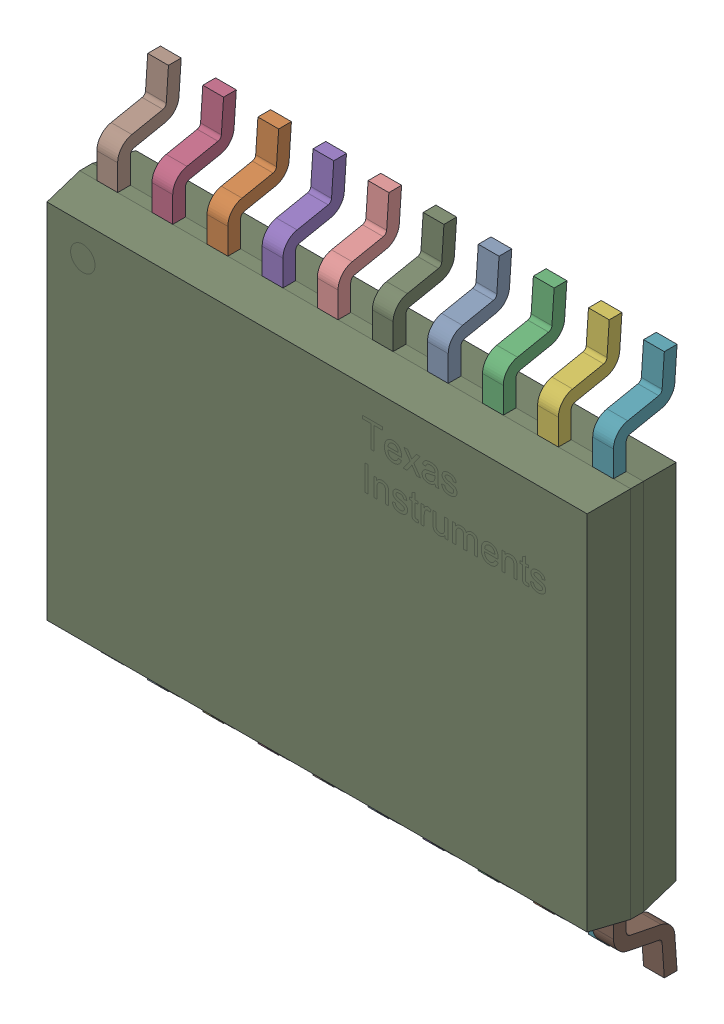
SolidWorks assembly Copy of IC_Texas_Instruments_TXS0108EQPWRQ1_eec^Copy of U3_PMPi-PCB, configuration Default. Lengths in mm.
Overall size (6.5 6.4 1.2).
21 component instances, 3 part files, 0 mates.
Components (placement in the parent):
- Copy of Texas Instruments TXS0108EQPWRQ1 2_MIR^Copy of IC_Texas_Instruments_TXS0108EQPWRQ1_eec_Copy of U3_PMPi-PCB-1: Copy of Texas Instruments TXS0108EQPWRQ1 2_MIR^Copy of IC_Texas_Instruments_TXS0108EQPWRQ1_eec_Copy of U3_PMPi-PCB [Default] at (2.2755 -1.1345 -0.3924) x (0 -1 0) z (-1 0 0) size (1 0.75 0.24)
- Copy of Texas Instruments TXS0108EQPWRQ1 2_MIR^Copy of IC_Texas_Instruments_TXS0108EQPWRQ1_eec_Copy of U3_PMPi-PCB-2: Copy of Texas Instruments TXS0108EQPWRQ1 2_MIR^Copy of IC_Texas_Instruments_TXS0108EQPWRQ1_eec_Copy of U3_PMPi-PCB [Default] at (-0.3245 -1.1345 -0.3924) x (0 -1 0) z (-1 0 0) size (1 0.75 0.24)
- Copy of Texas Instruments TXS0108EQPWRQ1 2_MIR^Copy of IC_Texas_Instruments_TXS0108EQPWRQ1_eec_Copy of U3_PMPi-PCB-3: Copy of Texas Instruments TXS0108EQPWRQ1 2_MIR^Copy of IC_Texas_Instruments_TXS0108EQPWRQ1_eec_Copy of U3_PMPi-PCB [Default] at (2.9255 -1.1345 -0.3924) x (0 -1 0) z (-1 0 0) size (1 0.75 0.24)
- Copy of Texas Instruments TXS0108EQPWRQ1 2_MIR^Copy of IC_Texas_Instruments_TXS0108EQPWRQ1_eec_Copy of U3_PMPi-PCB-4: Copy of Texas Instruments TXS0108EQPWRQ1 2_MIR^Copy of IC_Texas_Instruments_TXS0108EQPWRQ1_eec_Copy of U3_PMPi-PCB [Default] at (-0.9745 -1.1345 -0.3924) x (0 -1 0) z (-1 0 0) size (1 0.75 0.24)
- Copy of Texas Instruments TXS0108EQPWRQ1 2_MIR^Copy of IC_Texas_Instruments_TXS0108EQPWRQ1_eec_Copy of U3_PMPi-PCB-5: Copy of Texas Instruments TXS0108EQPWRQ1 2_MIR^Copy of IC_Texas_Instruments_TXS0108EQPWRQ1_eec_Copy of U3_PMPi-PCB [Default] at (0.3255 -1.1345 -0.3924) x (0 -1 0) z (-1 0 0) size (1 0.75 0.24)
- Copy of Texas Instruments TXS0108EQPWRQ1 2_MIR^Copy of IC_Texas_Instruments_TXS0108EQPWRQ1_eec_Copy of U3_PMPi-PCB-6: Copy of Texas Instruments TXS0108EQPWRQ1 2_MIR^Copy of IC_Texas_Instruments_TXS0108EQPWRQ1_eec_Copy of U3_PMPi-PCB [Default] at (3.5755 -1.1345 -0.3924) x (0 -1 0) z (-1 0 0) size (1 0.75 0.24)
- Copy of Texas Instruments TXS0108EQPWRQ1 2_MIR^Copy of IC_Texas_Instruments_TXS0108EQPWRQ1_eec_Copy of U3_PMPi-PCB-7: Copy of Texas Instruments TXS0108EQPWRQ1 2_MIR^Copy of IC_Texas_Instruments_TXS0108EQPWRQ1_eec_Copy of U3_PMPi-PCB [Default] at (4.2255 -1.1345 -0.3924) x (0 -1 0) z (-1 0 0) size (1 0.75 0.24)
- Copy of Texas Instruments TXS0108EQPWRQ1 2_MIR^Copy of IC_Texas_Instruments_TXS0108EQPWRQ1_eec_Copy of U3_PMPi-PCB-8: Copy of Texas Instruments TXS0108EQPWRQ1 2_MIR^Copy of IC_Texas_Instruments_TXS0108EQPWRQ1_eec_Copy of U3_PMPi-PCB [Default] at (-1.6245 -1.1345 -0.3924) x (0 -1 0) z (-1 0 0) size (1 0.75 0.24)
- Copy of Texas Instruments TXS0108EQPWRQ1 2_MIR^Copy of IC_Texas_Instruments_TXS0108EQPWRQ1_eec_Copy of U3_PMPi-PCB-9: Copy of Texas Instruments TXS0108EQPWRQ1 2_MIR^Copy of IC_Texas_Instruments_TXS0108EQPWRQ1_eec_Copy of U3_PMPi-PCB [Default] at (1.6255 -1.1345 -0.3924) x (0 -1 0) z (-1 0 0) size (1 0.75 0.24)
- Copy of Texas Instruments TXS0108EQPWRQ1 2_MIR^Copy of IC_Texas_Instruments_TXS0108EQPWRQ1_eec_Copy of U3_PMPi-PCB-10: Copy of Texas Instruments TXS0108EQPWRQ1 2_MIR^Copy of IC_Texas_Instruments_TXS0108EQPWRQ1_eec_Copy of U3_PMPi-PCB [Default] at (0.9755 -1.1345 -0.3924) x (0 -1 0) z (-1 0 0) size (1 0.75 0.24)
- Copy of Texas Instruments TXS0108EQPWRQ1 2^Copy of IC_Texas_Instruments_TXS0108EQPWRQ1_eec_Copy of U3_PMPi-PCB-1: Copy of Texas Instruments TXS0108EQPWRQ1 2^Copy of IC_Texas_Instruments_TXS0108EQPWRQ1_eec_Copy of U3_PMPi-PCB [Default] at (4.2255 -6.5345 -0.3924) x (0 1 0) z (1 0 0) size (1 0.75 0.24)
- Copy of Texas Instruments TXS0108EQPWRQ1 2^Copy of IC_Texas_Instruments_TXS0108EQPWRQ1_eec_Copy of U3_PMPi-PCB-2: Copy of Texas Instruments TXS0108EQPWRQ1 2^Copy of IC_Texas_Instruments_TXS0108EQPWRQ1_eec_Copy of U3_PMPi-PCB [Default] at (-1.6245 -6.5345 -0.3924) x (0 1 0) z (1 0 0) size (1 0.75 0.24)
- Copy of Texas Instruments TXS0108EQPWRQ1 2^Copy of IC_Texas_Instruments_TXS0108EQPWRQ1_eec_Copy of U3_PMPi-PCB-3: Copy of Texas Instruments TXS0108EQPWRQ1 2^Copy of IC_Texas_Instruments_TXS0108EQPWRQ1_eec_Copy of U3_PMPi-PCB [Default] at (0.9755 -6.5345 -0.3924) x (0 1 0) z (1 0 0) size (1 0.75 0.24)
- Copy of Texas Instruments TXS0108EQPWRQ1 2^Copy of IC_Texas_Instruments_TXS0108EQPWRQ1_eec_Copy of U3_PMPi-PCB-4: Copy of Texas Instruments TXS0108EQPWRQ1 2^Copy of IC_Texas_Instruments_TXS0108EQPWRQ1_eec_Copy of U3_PMPi-PCB [Default] at (2.9255 -6.5345 -0.3924) x (0 1 0) z (1 0 0) size (1 0.75 0.24)
- Copy of Texas Instruments TXS0108EQPWRQ1 2^Copy of IC_Texas_Instruments_TXS0108EQPWRQ1_eec_Copy of U3_PMPi-PCB-5: Copy of Texas Instruments TXS0108EQPWRQ1 2^Copy of IC_Texas_Instruments_TXS0108EQPWRQ1_eec_Copy of U3_PMPi-PCB [Default] at (2.2755 -6.5345 -0.3924) x (0 1 0) z (1 0 0) size (1 0.75 0.24)
- Copy of Texas Instruments TXS0108EQPWRQ1 2^Copy of IC_Texas_Instruments_TXS0108EQPWRQ1_eec_Copy of U3_PMPi-PCB-6: Copy of Texas Instruments TXS0108EQPWRQ1 2^Copy of IC_Texas_Instruments_TXS0108EQPWRQ1_eec_Copy of U3_PMPi-PCB [Default] at (-0.3245 -6.5345 -0.3924) x (0 1 0) z (1 0 0) size (1 0.75 0.24)
- Copy of Texas Instruments TXS0108EQPWRQ1 2^Copy of IC_Texas_Instruments_TXS0108EQPWRQ1_eec_Copy of U3_PMPi-PCB-7: Copy of Texas Instruments TXS0108EQPWRQ1 2^Copy of IC_Texas_Instruments_TXS0108EQPWRQ1_eec_Copy of U3_PMPi-PCB [Default] at (1.6255 -6.5345 -0.3924) x (0 1 0) z (1 0 0) size (1 0.75 0.24)
- Copy of Texas Instruments TXS0108EQPWRQ1 2^Copy of IC_Texas_Instruments_TXS0108EQPWRQ1_eec_Copy of U3_PMPi-PCB-8: Copy of Texas Instruments TXS0108EQPWRQ1 2^Copy of IC_Texas_Instruments_TXS0108EQPWRQ1_eec_Copy of U3_PMPi-PCB [Default] at (-0.9745 -6.5345 -0.3924) x (0 1 0) z (1 0 0) size (1 0.75 0.24)
- Copy of Texas Instruments TXS0108EQPWRQ1 2^Copy of IC_Texas_Instruments_TXS0108EQPWRQ1_eec_Copy of U3_PMPi-PCB-9: Copy of Texas Instruments TXS0108EQPWRQ1 2^Copy of IC_Texas_Instruments_TXS0108EQPWRQ1_eec_Copy of U3_PMPi-PCB [Default] at (3.5755 -6.5345 -0.3924) x (0 1 0) z (1 0 0) size (1 0.75 0.24)
- Copy of Texas Instruments TXS0108EQPWRQ1 2^Copy of IC_Texas_Instruments_TXS0108EQPWRQ1_eec_Copy of U3_PMPi-PCB-10: Copy of Texas Instruments TXS0108EQPWRQ1 2^Copy of IC_Texas_Instruments_TXS0108EQPWRQ1_eec_Copy of U3_PMPi-PCB [Default] at (0.3255 -6.5345 -0.3924) x (0 1 0) z (1 0 0) size (1 0.75 0.24)
- Copy of Texas Instruments TXS0108EQPWRQ1 1^Copy of IC_Texas_Instruments_TXS0108EQPWRQ1_eec_Copy of U3_PMPi-PCB-1: Copy of Texas Instruments TXS0108EQPWRQ1 1^Copy of IC_Texas_Instruments_TXS0108EQPWRQ1_eec_Copy of U3_PMPi-PCB [Default] at (1.423 -3.8345 -0.6174) size (6.5 4.4 1.05)
